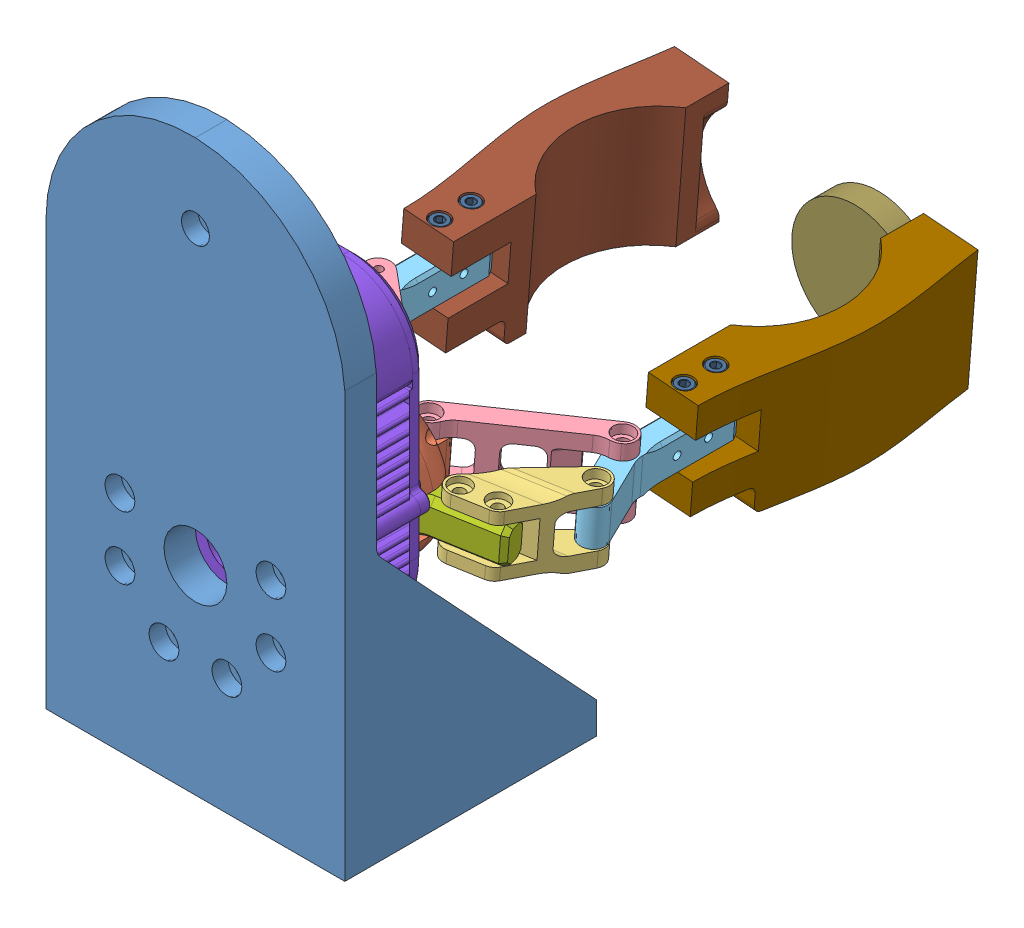
SolidWorks assembly Wrist 2, configuration Default. Lengths in mm.
Overall size (116.15 181.02 199.26).
26 component instances, 12 part files, 7 mates.
Components (placement in the parent):
- Wrist Bracket-1: Wrist Bracket [Default] at (0 -68.6171 71.1145) x (0 1 0) z (0 0 1) size (181.02 95 80)
- Gripper-1: Gripper [Default] at (-28.5941 111.8312 34.5551) x (0 1 0) z (-1 0 0) size (120.27 189.26 121.01) (flexible)
  - Hebi Motor with Gripper-1: Hebi Motor with Gripper [Default] at (-48.6457 -21.5594 3.9658) size (130.07 120.26 73.14) (flexible)
    - HEBI Robotics-A-2143-02-1: HEBI Robotics-A-2143-02 [Default] at (0 4.6253 0) x (0.079696 0 0.996819) z (-0.996819 0 0.079696) size (112.08 105.21 45) (flexible)
      - HEBI Robotics-A-2143-02_PM-2357-02-1: HEBI Robotics-A-2143-02_PM-2357-02 [Default] at (0 30.9247 0) x (0 0 -1) z (1 0 0) size (45 28 44.67)
      - HEBI Robotics-A-2143-02_PM-2358-02-1: HEBI Robotics-A-2143-02_PM-2358-02 [Default] at (-31.436 29.5333 0) x (0 0 -1) z (0.966127 -0.258068 0) size (23 26 33)
      - HEBI Robotics-A-2143-02_PM-2358-02-2: HEBI Robotics-A-2143-02_PM-2358-02 [Default] at (31.4354 29.5354 0) x (0 0 1) z (-0.966125 -0.258076 0) size (23 26 33)
      - HEBI Robotics-A-2143-02_PM-2359-02-1: HEBI Robotics-A-2143-02_PM-2359-02 [Default] at (21.9996 52.7813 0) x (0 0 1) z (0.775123 0.631811 0) size (23 8 51.86)
      - HEBI Robotics-A-2143-02_PM-2359-02-2: HEBI Robotics-A-2143-02_PM-2359-02 [Default] at (-22.0004 52.7803 0) x (0 0 -1) z (-0.775159 0.631767 0) size (23 8 51.86)
      - HEBI Robotics-A-2143-02_PM-2360-02-1: HEBI Robotics-A-2143-02_PM-2360-02 [Default] at (-39.0008 66.6359 0) x (-1 -0.000025 0) z (0 0 -1) size (15.5 54 12.08)
      - HEBI Robotics-A-2143-02_PM-2360-02-2: HEBI Robotics-A-2143-02_PM-2360-02 [Default] at (38.9992 66.6378 0) x (1 0.000025 0) z (0 0 1) size (15.5 54 12.08)
      - HEBI Robotics-A-2055-01_PM-2218-01-1: HEBI Robotics-A-2055-01_PM-2218-01 [Default] at (0 11.4247 0) size (45 32.5 45)
      - HEBI Robotics-A-2055-01_PM-2221-01-1: HEBI Robotics-A-2055-01_PM-2221-01 [Default] at (12.5 22.9247 0) x (0.966125 0.258076 0) z (0 0 1) size (35.49 9.86 12)
      - HEBI Robotics-A-2055-01_PM-2221-01-2: HEBI Robotics-A-2055-01_PM-2221-01 [Default] at (-12.5 22.9247 0) x (-0.966162 0.257934 0) z (0 0 -1) size (35.49 9.86 12)
    - HEBI Robotics-X5-Export-2021-1: HEBI Robotics-X5-Export-2021 [Default] x (1 0 0) z (0 1 0) size (109.71 73.14 31.05)
  - gripper finger-1: gripper finger [Default] at (-33.7178 115.2018 -10.0826) x (0.079696 0 0.996819) z (0 -1 0) size (25.6 40 87.5)
  - 91292A114_M3-0.5x12-1: 91292A114_M3-0.5x12 [91292A114] at (-52.5514 78.7018 -34.8479) x (-0.073904 -0.374262 -0.924373) z (0.996819 0 -0.079696) size (5.5 5.5 15.23)
  - 91292A114_M3-0.5x12-2: 91292A114_M3-0.5x12 [91292A114] at (-52.5514 68.7018 -34.8479) x (-0.068939 -0.501733 -0.862271) z (0.996819 0 -0.079696) size (5.5 5.5 15.23)
  - 91292A114_M3-0.5x12-4: 91292A114_M3-0.5x12 [91292A114] at (-50.9565 78.7018 -34.9754) x (-0.009824 -0.992373 -0.122882) z (-0.996819 0 0.079696) size (5.5 5.5 15.23)
  - 91292A114_M3-0.5x12-6: 91292A114_M3-0.5x12 [91292A114] at (-50.9565 68.7018 -34.9754) x (0.004564 -0.998359 0.057085) z (-0.996819 0 0.079696) size (5.5 5.5 15.23)
  - gripper finger mirror-1: gripper finger mirror [Default] at (-31.6757 115.2031 15.46) x (0.079696 0.000026 0.996819) z (0.000002 -1 0.000026) size (25.6 40 87.5)
  - 91292A114_M3-0.5x12-15: 91292A114_M3-0.5x12 [91292A114] at (-46.3351 78.7037 42.904) x (-0.068939 -0.501733 -0.862271) z (0.996819 0 -0.079696) size (5.5 5.5 15.23)
  - 91292A114_M3-0.5x12-17: 91292A114_M3-0.5x12 [91292A114] at (-46.3351 68.7037 42.9043) x (-0.063937 -0.596967 -0.799714) z (0.996819 0 -0.079696) size (5.5 5.5 15.23)
  - 91292A114_M3-0.5x12-20: 91292A114_M3-0.5x12 [91292A114] at (-44.7402 78.7037 42.7765) x (0.004564 -0.998359 0.057085) z (-0.996819 0 0.079696) size (5.5 5.5 15.23)
  - 91292A114_M3-0.5x12-22: 91292A114_M3-0.5x12 [91292A114] at (-44.7402 68.7037 42.7768) x (0.019011 -0.971131 0.237787) z (-0.996819 0 0.079696) size (5.5 5.5 15.23)
- Checker_40mm-1: Checker_40mm [Default] at (-14.7647 55.5932 -118.1467) x (1 0 0) z (0 -1 0) size (40 7.5 40)
Mates (geometry in assembly coordinates):
- Coincident1: coincident anti-aligned: plane of Wrist Bracket-1 through (0 -68.6171 71.1145) normal (-1 0 0)
- Coincident2: coincident anti-aligned: plane of Wrist Bracket-1 through (-80.0599 0 81.1145) normal (0 -1 0)
- Coincident3: coincident anti-aligned: plane of Wrist Bracket-1 through (-34.1375 131.8466 71.1145) normal (0 0 -1); plane of Gripper-1/Hebi Motor with Gripper-1/HEBI Robotics-X5-Export-2021-1 through (-32.5599 63.1855 71.1145) normal (0 0 1)
- Concentric1: concentric aligned: cylinder of Wrist Bracket-1 through (-32.5599 63.1855 81.1145) axis (0 0 -1) radius 10; cylinder of Gripper-1/Hebi Motor with Gripper-1/HEBI Robotics-X5-Export-2021-1 through (-32.5599 63.1855 66.1357) axis (0 0 -1) radius 7.5
- Coincident4: coincident aligned: plane of Gripper-1/gripper finger-1 through (-18.5116 78.1134 -118.1467) normal (0 0 -1); plane of Checker_40mm-1 through (-14.7647 55.5932 -118.1467) normal (0 0 -1)
- Concentric2: concentric aligned: cylinder of Gripper-1/gripper finger-1 through (-14.7647 55.5932 -110.6467) axis (0 0 -1) radius 20; cylinder of Checker_40mm-1 through (-14.7647 55.5932 -110.6467) axis (0 0 -1) radius 20
- Concentric3: concentric aligned: cylinder of Wrist Bracket-1 through (-8.5599 71.1855 75.9145) axis (0 0 1) radius 4.75; cylinder of Gripper-1/Hebi Motor with Gripper-1/HEBI Robotics-X5-Export-2021-1 through (-8.5599 71.1855 71.1145) axis (0 0 1) radius 2.1
